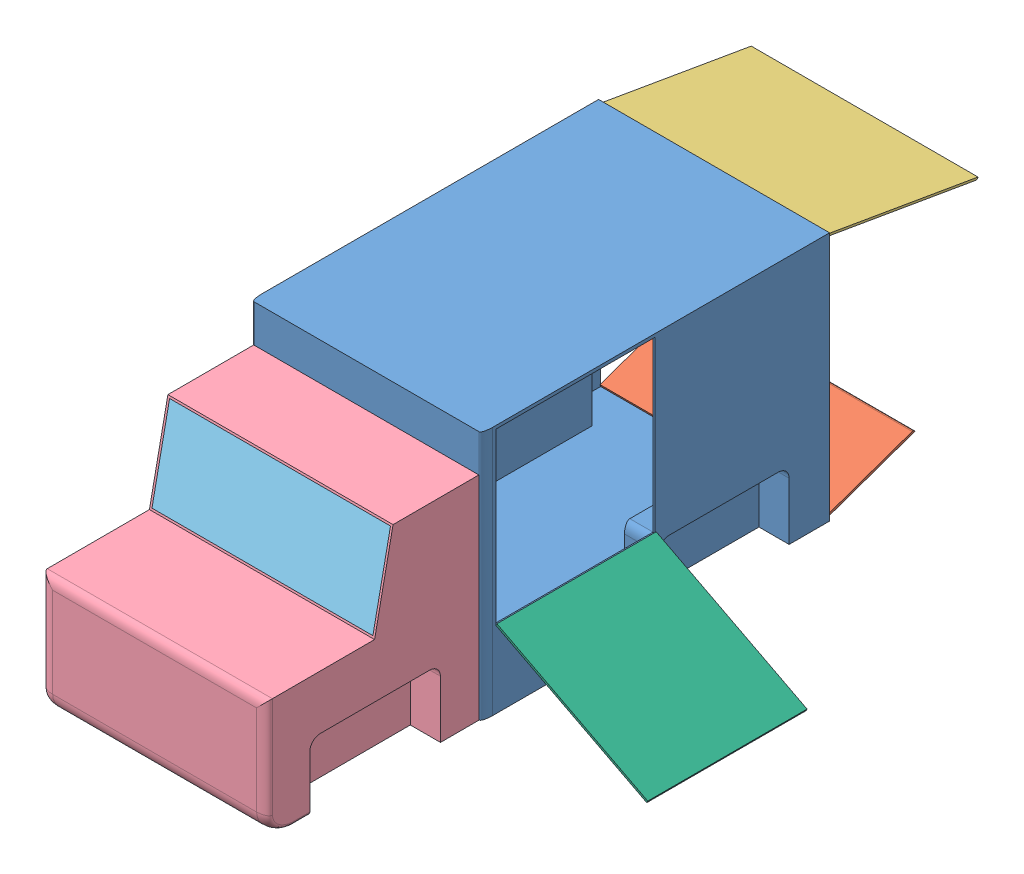
SolidWorks assembly Full_car, configuration Default. Lengths in mm.
Overall size (360.61 294.15 668.96).
6 component instances, 6 part files, 11 mates.
Components (placement in the parent):
- Backside_trunk-1: Backside_trunk [Default] at (-134.8409 -112.0335 173.62) size (217.7 235.3 327.3)
- Lower_back_door-1: Lower_back_door [Default] at (-134.8409 -110.6977 -151.6935) x (-1 0 0) z (0 -0.943247 -0.332093) size (213.5 87.28 2)
- Top_back_door-1: Top_back_door [Default] at (0.9182 350.8841 -315.1403) x (1 0 0) z (0 0.745643 0.666346) size (213.5 91 113.07)
- Front-2: Front [Default] at (-26.0909 -67.2367 -254.8196) x (0 0 1) z (-1 0 0) size (199.73 200.32 214.58)
- Glass_pane-1: Glass_pane [Default] at (-26.0909 39.0204 264.6674) x (1 0 0) z (0 0.200393 0.979716) size (208 82.78 2)
- Side_door-1: Side_door [Default] at (18.6293 -6.7885 173.62) x (0 0 -1) z (-0.459709 -0.888069 0) size (150 160 2)
Mates (geometry in assembly coordinates):
- Coincident4: coincident aligned: line of Backside_trunk-1 through (80.6591 -110.0335 -153.58) axis (-1 0 0); line of Lower_back_door-1 through (80.6591 -110.0335 -153.58) axis (-1 0 0)
- Coincident5: coincident: point of Backside_trunk-1; point of Lower_back_door-1
- Coincident6: coincident anti-aligned: line of Backside_trunk-1 through (80.6591 121.0665 -153.58) axis (-1 0 0); line of Top_back_door-1 through (-132.8409 121.0665 -153.58) axis (1 0 0)
- Coincident7: coincident: point of Backside_trunk-1; point of Top_back_door-1
- Coincident38: coincident aligned: line of Backside_trunk-1 through (-132.0909 -112.0335 173.62) axis (1 0 0); line of Front-2 through (-132.0909 -112.0335 173.62) axis (1 0 0)
- InPlace1: in place: plane of Front-2 through (-132.0909 2.84 272.0678) normal (0 0.200393 0.979716); plane of ? through (0 53.5287 261.6998) normal (0 0.200393 0.979716); moOrthogonalPlaneRef_w of Front-2 through (-132.0909 2.84 272.0678) normal (0 0.200393 0.979716); plane of ? through (0 53.5287 261.6998) normal (0 0.979716 -0.200393); plane of Front-2 through (-132.0909 2.84 272.0678) normal (0 0.200393 0.979716); plane of ? through (0 53.5287 261.6998) normal (1 0 0); plane of Front-2 through (-132.0909 2.84 272.0678) normal (0 0.200393 0.979716); unknown of Glass_pane-1
- Coincident39: coincident aligned: plane of Front-2; plane of Glass_pane-1
- Coincident40: coincident aligned: moOrthogonalPlaneRef_w of Front-2 through (-26.0909 39.0204 264.6674) normal (0 0.979716 -0.200393); plane of Glass_pane-1 through (-26.0909 39.0204 264.6674) normal (0 0.979716 -0.200393)
- Coincident41: coincident anti-aligned: moOrthogonalPlaneRef_w of Front-2 through (-26.0909 39.0204 264.6674) normal (-1 0 0); plane of Glass_pane-1 through (-26.0909 39.0204 264.6674) normal (1 0 0)
- Coincident39: coincident: point of Backside_trunk-1; point of Side_door-1
- Coincident40: coincident aligned: line of Backside_trunk-1 through (82.6591 -39.9335 160.62) axis (0 0 -1); line of Side_door-1 through (82.6591 -39.9335 160.62) axis (0 0 -1)
